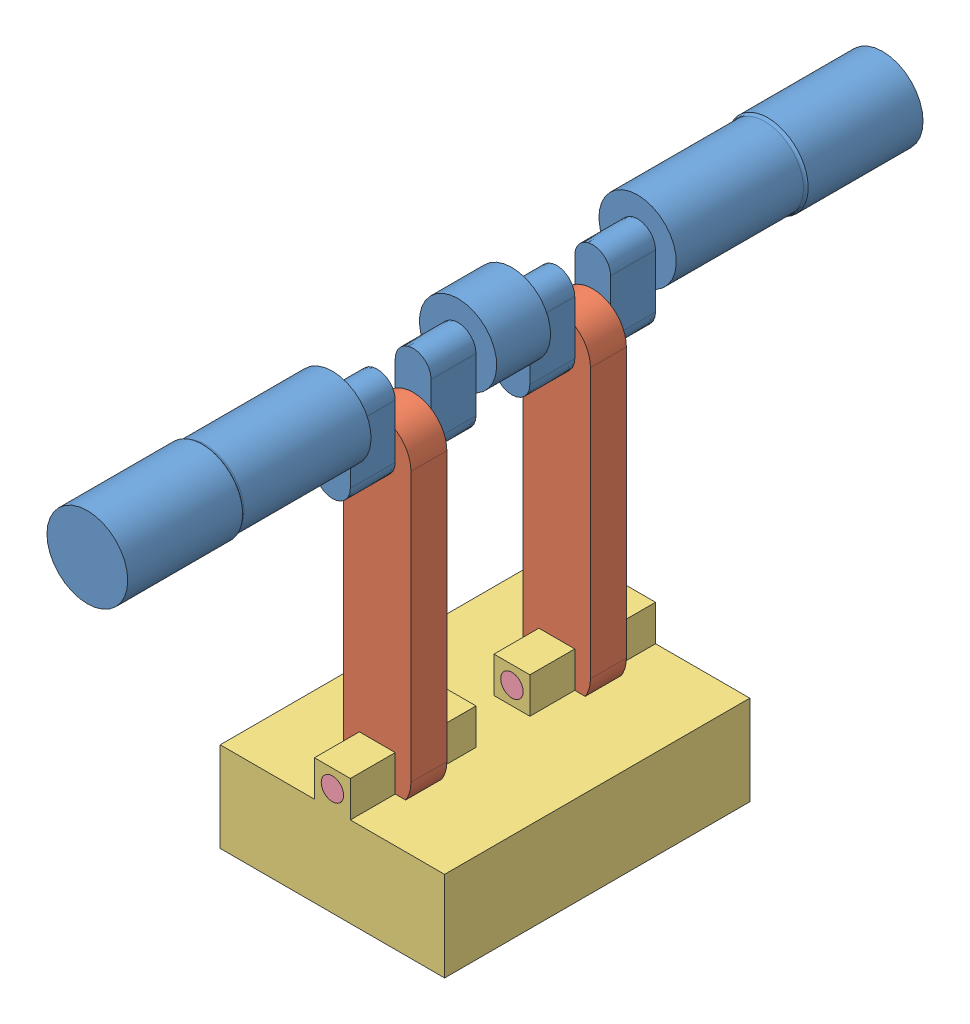
SolidWorks assembly subassemblynew, configuration Default. Lengths in mm.
Overall size (250 535 886).
6 component instances, 4 part files, 9 mates.
Components (placement in the parent):
- crankshaftnew-1: crankshaftnew [Default] at (83.1221 287.7704 264.8274) x (1 0 0) z (0 -1 0) size (110 886 135)
- conrodnew-1: conrodnew [Default] at (83.1221 227.7704 699.8274) x (0 -1 0) z (1 0 0) size (375 40 75)
- conrodnew-2: conrodnew [Default] at (83.1221 227.7704 459.8274) x (0 -1 0) z (-1 0 0) size (375 40 75)
- ram-1: ram [Default] at (-41.8779 -192.2296 409.8274) size (250 140 340)
- pin-1: pin [Default] at (83.1221 -72.2296 609.8274) x (-0.923728 -0.383049 0) z (-0.383049 0.923728 0) size (25 140 25)
- pin-2: pin [Default] at (83.1221 -72.2296 549.8274) x (1 0 0) z (0 1 0) size (25 140 25)
Mates (geometry in assembly coordinates):
- Coincident1: coincident anti-aligned: circle of crankshaftnew-1; circle of conrodnew-1
- Parallel1: parallel anti-aligned: line of crankshaftnew-1 through (103.1221 227.7704 749.8274) axis (0 1 0); line of conrodnew-1 through (120.6221 227.7704 699.8274) axis (0 -1 0)
- Coincident3: coincident aligned: circle of crankshaftnew-1; circle of conrodnew-2
- Parallel2: parallel aligned: line of crankshaftnew-1 through (103.1221 227.7704 499.8274) axis (0 1 0); line of conrodnew-2 through (120.6221 -72.2296 459.8274) axis (0 1 0)
- Coincident5: coincident aligned: circle of conrodnew-1; circle of ram-1
- Concentric1: concentric aligned: circle of ram-1; circle of pin-1
- Coincident7: coincident aligned: plane of ram-1 through (-41.8779 -92.2296 749.8274) normal (0 0 1); plane of pin-1 through (83.1221 -72.2296 749.8274) normal (0 0 1)
- Concentric2: concentric anti-aligned: circle of ram-1; circle of pin-2
- Coincident9: coincident aligned: plane of ram-1 through (63.1221 -92.2296 549.8274) normal (0 0 1); plane of pin-2 through (83.1221 -72.2296 549.8274) normal (0 0 1)
